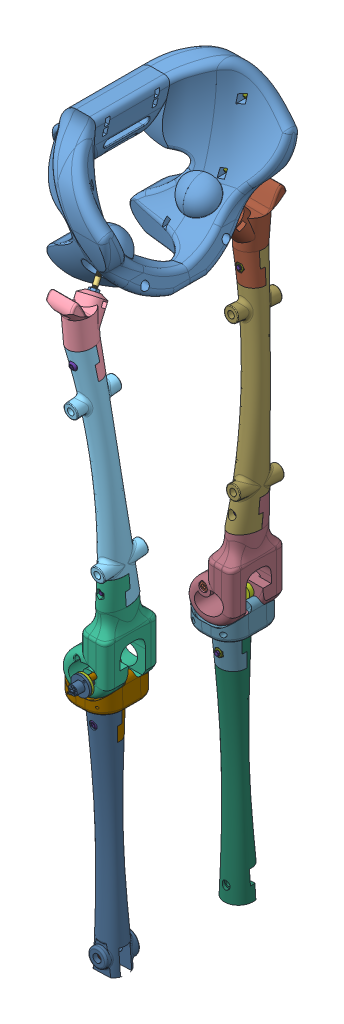
SolidWorks assembly 10_BipedalRobot_Assembly_wHardware, configuration Default. Lengths in mm.
Overall size (197.88 962.44 296.88).
85 component instances, 30 part files, 145 mates.
Components (placement in the parent):
- 09_BipedalRobot_Assembly-1: 09_BipedalRobot_Assembly [Default] at origin size (197.88 962.44 294.61) (flexible)
  - 02_01_Pelvis-1: 02_01_Pelvis [Default] at origin size (197.88 220.17 282.18)
  - 6630T310_METRIC BLACK POLYPROPYLENE BALL KNOB-1: 6630T310_METRIC BLACK POLYPROPYLENE BALL KNOB [6630T31] at (-58.671 -58.8069 72.4936) x (0.804974 0.48308 0.344458) z (-0.194905 0.763657 -0.6155) size (38 38 37.9)
  - 92997A108_CORROSION-RESISTANT SETUP STUD-1: 92997A108_CORROSION-RESISTANT SETUP STUD [92997A108] at (-55.0653 -72.9345 83.8804) x (0.017759 0.630179 0.776247) z (0.194905 -0.763657 0.6155) size (6.34 6.15 50.8)
  - 03_02_FemurHead_Right-1: 03_02_FemurHead_Right [Default] at (-45.3395 -121.5667 106.123) x (1 0 0) z (0 -0.087156 0.996195) size (46.92 105.86 63.35)
  - 03_01_FemurBone_Right-1: 03_01_FemurBone_Right [Default] at (-44.1058 -425.8587 87.0078) x (1 0 0) z (0 -0.087156 0.996195) size (54.81 304.92 60)
  - 04_01_KneeTop_Right-1: 04_01_KneeTop_Right [Default] at (-35.6321 -504.5163 84.7583) size (77.56 157.24 74.14)
  - 04_05_BackLink-1: 04_05_BackLink [Default] at (-42.5577 -521.5571 84.8583) x (0.712112 0.702066 0) z (0 0 1) size (62.75 16 5.9)
  - 04_06_FrontLink-1: 04_06_FrontLink [Default] at (-31.6099 -512.6089 78.7583) x (0.469804 -0.882771 0) z (0 0 1) size (67.43 16 3.9)
  - 04_02_KneeBottom_Right-1: 04_02_KneeBottom_Right [Default] at (-43.0474 -546.2764 84.7583) x (0.999391 0.034899 0) z (0 0 1) size (78.49 85.12 75.75)
  - 05_01_Tibial_Right-1: 05_01_Tibial_Right [Default] at (-42.6984 -556.2703 84.7583) x (0.999391 0.034899 0) z (0 0 1) size (38.19 305.23 41.5)
  - 6630T310_METRIC BLACK POLYPROPYLENE BALL KNOB-2: 6630T310_METRIC BLACK POLYPROPYLENE BALL KNOB [6630T31] at (-58.671 -58.8069 -72.4936) x (0.963134 0.030376 0.2673) z (-0.194905 0.763657 0.6155) size (38 38 37.9)
  - 92997A108_CORROSION-RESISTANT SETUP STUD-2: 92997A108_CORROSION-RESISTANT SETUP STUD [92997A108] at (-55.0653 -72.9345 -83.8804) x (-0.54916 -0.604916 0.576628) z (-0.194905 0.763657 0.6155) size (6.34 6.15 50.8)
  - 03_04_FemurHead_Left-1: 03_04_FemurHead_Left [Default] at (-45.3395 -121.5667 -106.123) x (1 0 0) z (0 0.087156 0.996195) size (46.92 105.86 63.35)
  - 03_03_FemurBone_Left-1: 03_03_FemurBone_Left [Default] at (-44.1058 -425.8587 -87.0078) x (1 0 0) z (0 0.087156 0.996195) size (54.81 304.92 60)
  - 04_03_KneeTop_Left-1: 04_03_KneeTop_Left [Default] at (-35.6321 -504.5163 -84.7583) size (77.56 157.24 74.14)
  - 04_05_BackLink-2: 04_05_BackLink [Default] at (-42.5577 -521.5571 -90.7583) x (0.712112 0.702066 0) z (0 0 1) size (62.75 16 5.9)
  - 04_06_FrontLink-2: 04_06_FrontLink [Default] at (-31.6099 -512.6089 -82.6583) x (-0.469804 0.882771 0) z (0 0 1) size (67.43 16 3.9)
  - 04_04_KneeBottom_Left-1: 04_04_KneeBottom_Left [Default] at (-43.0474 -546.2764 -84.8583) x (0.999391 0.034899 0) z (0 0 1) size (78.49 85.12 75.75)
  - 05_02_Tibial_Left-1: 05_02_Tibial_Left [Default] at (-42.6984 -556.2703 -84.8583) x (0.999391 0.034899 0) z (0 0 1) size (38.19 304.9 38.19)
- 94645A205_HIGH-STRENGTH STEEL NYLON-INSERT LOCKNUT-1: 94645A205_HIGH-STRENGTH STEEL NYLON-INSERT LOCKNUT [94645A205] at (-47.544 52.8275 110.8479) x (0 -1 0) z (0 0 1) size (10 6.41 11.55)
- 94645A205_HIGH-STRENGTH STEEL NYLON-INSERT LOCKNUT-2: 94645A205_HIGH-STRENGTH STEEL NYLON-INSERT LOCKNUT [94645A205] at (-47.544 -21.0136 84.8541) x (0 -1 0) z (0 0 1) size (10 6.41 11.55)
- 94645A205_HIGH-STRENGTH STEEL NYLON-INSERT LOCKNUT-4: 94645A205_HIGH-STRENGTH STEEL NYLON-INSERT LOCKNUT [94645A205] at (-74.544 -75.4386 54.7323) x (0 1 0) z (0 0 1) size (10 6.41 11.55)
- 94645A205_HIGH-STRENGTH STEEL NYLON-INSERT LOCKNUT-6: 94645A205_HIGH-STRENGTH STEEL NYLON-INSERT LOCKNUT [94645A205] at (-47.544 52.8275 -110.8479) x (0 1 0) z (0 0 -1) size (10 6.41 11.55)
- 94645A205_HIGH-STRENGTH STEEL NYLON-INSERT LOCKNUT-8: 94645A205_HIGH-STRENGTH STEEL NYLON-INSERT LOCKNUT [94645A205] at (-47.544 -21.0136 -84.8541) x (0 1 0) z (0 0 -1) size (10 6.41 11.55)
- 94645A205_HIGH-STRENGTH STEEL NYLON-INSERT LOCKNUT-10: 94645A205_HIGH-STRENGTH STEEL NYLON-INSERT LOCKNUT [94645A205] at (-74.544 -75.4386 -54.7323) x (0 1 0) z (0 0 1) size (10 6.41 11.55)
- 94645A205_HIGH-STRENGTH STEEL NYLON-INSERT LOCKNUT-12: 94645A205_HIGH-STRENGTH STEEL NYLON-INSERT LOCKNUT [94645A205] at (-104.3146 69.6752 36.5) x (0 1 0) z (-1 0 0) size (10 6.41 11.55)
- 94645A205_HIGH-STRENGTH STEEL NYLON-INSERT LOCKNUT-14: 94645A205_HIGH-STRENGTH STEEL NYLON-INSERT LOCKNUT [94645A205] at (-121.884 56.6312 36.5) x (0 1 0) z (-1 0 0) size (10 6.41 11.55)
- 94645A205_HIGH-STRENGTH STEEL NYLON-INSERT LOCKNUT-16: 94645A205_HIGH-STRENGTH STEEL NYLON-INSERT LOCKNUT [94645A205] at (-121.884 56.6312 -30.5) x (0 1 0) z (-1 0 0) size (10 6.41 11.55)
- 94645A205_HIGH-STRENGTH STEEL NYLON-INSERT LOCKNUT-18: 94645A205_HIGH-STRENGTH STEEL NYLON-INSERT LOCKNUT [94645A205] at (-104.3146 69.6752 -30.5) x (0 1 0) z (-1 0 0) size (10 6.41 11.55)
- 94645A205_HIGH-STRENGTH STEEL NYLON-INSERT LOCKNUT-20: 94645A205_HIGH-STRENGTH STEEL NYLON-INSERT LOCKNUT [94645A205] at (-51.8494 -85.5349 94.0361) x (0.194905 0.645175 0.738757) z (0.961262 0.024023 -0.274588) size (10 6.41 11.55)
- 94645A205_HIGH-STRENGTH STEEL NYLON-INSERT LOCKNUT-22: 94645A205_HIGH-STRENGTH STEEL NYLON-INSERT LOCKNUT [94645A205] at (-51.8494 -85.5349 -94.0361) x (0.194905 0.645175 -0.738757) z (-0.961262 -0.024023 -0.274588) size (10 6.41 11.55)
- 94645A205_HIGH-STRENGTH STEEL NYLON-INSERT LOCKNUT-24: 94645A205_HIGH-STRENGTH STEEL NYLON-INSERT LOCKNUT [94645A205] at (-30.2115 -92.3012 -13.5) x (0.866025 -0.5 0) z (0.5 0.866025 0) size (10 6.41 11.55)
- 94645A205_HIGH-STRENGTH STEEL NYLON-INSERT LOCKNUT-26: 94645A205_HIGH-STRENGTH STEEL NYLON-INSERT LOCKNUT [94645A205] at (-41.8015 -140.2036 100.5688) x (0.866025 -0.498097 -0.043578) z (0.5 0.86273 0.075479) size (10 6.41 11.55)
- 94645A205_HIGH-STRENGTH STEEL NYLON-INSERT LOCKNUT-28: 94645A205_HIGH-STRENGTH STEEL NYLON-INSERT LOCKNUT [94645A205] at (-41.8015 -140.2036 -100.5688) x (0.866025 -0.498097 0.043578) z (-0.5 -0.86273 0.075479) size (10 6.41 11.55)
- 94645A205_HIGH-STRENGTH STEEL NYLON-INSERT LOCKNUT-30: 94645A205_HIGH-STRENGTH STEEL NYLON-INSERT LOCKNUT [94645A205] at (-23.6321 -408.0461 -101.9838) x (1 0 0) z (0 0.996195 -0.087156) size (10 6.41 11.55)
- 94645A205_HIGH-STRENGTH STEEL NYLON-INSERT LOCKNUT-36: 94645A205_HIGH-STRENGTH STEEL NYLON-INSERT LOCKNUT [94645A205] at (-41.8513 -575.3023 71.7583) x (0.999391 0.034899 0) z (-0.034899 0.999391 0) size (10 6.41 11.55)
- 94645A205_HIGH-STRENGTH STEEL NYLON-INSERT LOCKNUT-39: 94645A205_HIGH-STRENGTH STEEL NYLON-INSERT LOCKNUT [94645A205] at (-23.6321 -408.0461 101.9838) x (-0.5 0.86273 0.075479) z (0.866025 0.498097 0.043578) size (10 6.41 11.55)
- 94645A205_HIGH-STRENGTH STEEL NYLON-INSERT LOCKNUT-41: 94645A205_HIGH-STRENGTH STEEL NYLON-INSERT LOCKNUT [94645A205] at (-41.8513 -575.3023 -71.8583) x (0.999391 0.034899 0) z (0.034899 -0.999391 0) size (10 6.41 11.55)
- 91239A330_CLASS 10.9 STL BUTTON-HEAD SOCKET CAP SCREW-1: 91239A330_CLASS 10.9 STL BUTTON-HEAD SOCKET CAP SCREW [91239A330] at (-121.884 56.6312 66.8) size (10.5 10.5 38.95)
- 91239A330_CLASS 10.9 STL BUTTON-HEAD SOCKET CAP SCREW-2: 91239A330_CLASS 10.9 STL BUTTON-HEAD SOCKET CAP SCREW [91239A330] at (-77.844 52.8275 110.8479) x (0 0 1) z (-1 0 0) size (10.5 10.5 38.95)
- 91239A330_CLASS 10.9 STL BUTTON-HEAD SOCKET CAP SCREW-4: 91239A330_CLASS 10.9 STL BUTTON-HEAD SOCKET CAP SCREW [91239A330] at (-104.3146 69.6752 66.8) x (0.959125 0.282984 0) z (0 0 1) size (10.5 10.5 38.95)
- 91239A330_CLASS 10.9 STL BUTTON-HEAD SOCKET CAP SCREW-6: 91239A330_CLASS 10.9 STL BUTTON-HEAD SOCKET CAP SCREW [91239A330] at (-104.3146 69.6752 -66.8) x (-0.5 0.866025 0) z (0 0 -1) size (10.5 10.5 38.95)
- 91239A330_CLASS 10.9 STL BUTTON-HEAD SOCKET CAP SCREW-8: 91239A330_CLASS 10.9 STL BUTTON-HEAD SOCKET CAP SCREW [91239A330] at (-121.884 56.6312 -66.8) x (-0.642788 0.766044 0) z (0 0 -1) size (10.5 10.5 38.95)
- 91239A330_CLASS 10.9 STL BUTTON-HEAD SOCKET CAP SCREW-10: 91239A330_CLASS 10.9 STL BUTTON-HEAD SOCKET CAP SCREW [91239A330] at (-77.844 52.8275 -110.8479) x (0 0 1) z (-1 0 0) size (10.5 10.5 38.95)
- 91239A330_CLASS 10.9 STL BUTTON-HEAD SOCKET CAP SCREW-12: 91239A330_CLASS 10.9 STL BUTTON-HEAD SOCKET CAP SCREW [91239A330] at (-77.844 -21.0136 -84.8541) x (0 0 1) z (-1 0 0) size (10.5 10.5 38.95)
- 91239A330_CLASS 10.9 STL BUTTON-HEAD SOCKET CAP SCREW-14: 91239A330_CLASS 10.9 STL BUTTON-HEAD SOCKET CAP SCREW [91239A330] at (-77.844 -21.0136 84.8541) x (0 0 1) z (-1 0 0) size (10.5 10.5 38.95)
- 91239A330_CLASS 10.9 STL BUTTON-HEAD SOCKET CAP SCREW-16: 91239A330_CLASS 10.9 STL BUTTON-HEAD SOCKET CAP SCREW [91239A330] at (-44.244 -75.4386 -54.7323) x (0 0.171049 -0.985262) z (1 0 0) size (10.5 10.5 38.95)
- 91239A330_CLASS 10.9 STL BUTTON-HEAD SOCKET CAP SCREW-18: 91239A330_CLASS 10.9 STL BUTTON-HEAD SOCKET CAP SCREW [91239A330] at (-44.244 -75.4386 54.7323) x (0 0 -1) z (1 0 0) size (10.5 10.5 38.95)
- 91239A330_CLASS 10.9 STL BUTTON-HEAD SOCKET CAP SCREW-20: 91239A330_CLASS 10.9 STL BUTTON-HEAD SOCKET CAP SCREW [91239A330] at (-30.2115 -92.3012 16.8) x (0.985697 -0.168526 0) z (0 0 1) size (10.5 10.5 38.95)
- 91239A330_CLASS 10.9 STL BUTTON-HEAD SOCKET CAP SCREW-22: 91239A330_CLASS 10.9 STL BUTTON-HEAD SOCKET CAP SCREW [91239A330] at (-41.8015 -142.9042 131.4369) x (0.92579 -0.376599 -0.032948) z (0 -0.087156 0.996195) size (10.5 10.5 38.95)
- 91239A330_CLASS 10.9 STL BUTTON-HEAD SOCKET CAP SCREW-24: 91239A330_CLASS 10.9 STL BUTTON-HEAD SOCKET CAP SCREW [91239A330] at (-41.8015 -142.9042 -131.4369) x (-0.916799 -0.39783 0.034806) z (0 -0.087156 -0.996195) size (10.5 10.5 38.95)
- 91239A330_CLASS 10.9 STL BUTTON-HEAD SOCKET CAP SCREW-26: 91239A330_CLASS 10.9 STL BUTTON-HEAD SOCKET CAP SCREW [91239A330] at (-23.6321 -405.415 -71.9097) x (0.92535 -0.377672 0.033042) z (0 0.087156 0.996195) size (10.5 10.5 38.95)
- 91239A330_CLASS 10.9 STL BUTTON-HEAD SOCKET CAP SCREW-28: 91239A330_CLASS 10.9 STL BUTTON-HEAD SOCKET CAP SCREW [91239A330] at (-23.6321 -405.415 71.9097) x (-0.509415 -0.857247 -0.074999) z (0 0.087156 -0.996195) size (10.5 10.5 38.95)
- 91239A330_CLASS 10.9 STL BUTTON-HEAD SOCKET CAP SCREW-30: 91239A330_CLASS 10.9 STL BUTTON-HEAD SOCKET CAP SCREW [91239A330] at (-41.8513 -575.3023 -102.1583) x (-0.5 -0.866025 0) z (0 0 -1) size (10.5 10.5 38.95)
- 91239A330_CLASS 10.9 STL BUTTON-HEAD SOCKET CAP SCREW-32: 91239A330_CLASS 10.9 STL BUTTON-HEAD SOCKET CAP SCREW [91239A330] at (-41.8513 -575.3023 102.0583) x (-0.675882 0.73701 0) z (0 0 1) size (10.5 10.5 38.95)
- 91595A476_METRIC ALLOY STEEL DOWEL PIN-1: 91595A476_METRIC ALLOY STEEL DOWEL PIN [91595A476] at (-60.794 24.9417 100.1676) x (1 0 0) z (0 0.020434 0.999791) size (40 6 6)
- 91595A476_METRIC ALLOY STEEL DOWEL PIN-2: 91595A476_METRIC ALLOY STEEL DOWEL PIN [91595A476] at (-60.794 -3.0834 90.0569) x (1 0 0) z (0 -0.138344 0.990384) size (40 6 6)
- 91595A476_METRIC ALLOY STEEL DOWEL PIN-4: 91595A476_METRIC ALLOY STEEL DOWEL PIN [91595A476] at (-60.794 -93.1682 40.0283) x (1 0 0) z (0 -0.263326 0.964707) size (40 6 6)
- 91595A476_METRIC ALLOY STEEL DOWEL PIN-6: 91595A476_METRIC ALLOY STEEL DOWEL PIN [91595A476] at (-60.794 -93.1682 -40.0283) x (1 0 0) z (0 -0.780184 0.62555) size (40 6 6)
- 91595A476_METRIC ALLOY STEEL DOWEL PIN-8: 91595A476_METRIC ALLOY STEEL DOWEL PIN [91595A476] at (-61.544 -3.0834 -90.0569) x (-1 0 0) z (0 0.779019 -0.627) size (40 6 6)
- 91595A476_METRIC ALLOY STEEL DOWEL PIN-10: 91595A476_METRIC ALLOY STEEL DOWEL PIN [91595A476] at (-60.794 24.9417 -100.1676) x (1 0 0) z (0 -0.947084 0.320986) size (40 6 6)
- 90695A038_CLASS 04 STEEL THIN HEX NUT - DIN 439B-1: 90695A038_CLASS 04 STEEL THIN HEX NUT - DIN 439B [90695A038] at (-53.3306 -79.7311 89.3583) x (0.978461 0.194905 -0.06802) z (-0.06802 0.6155 0.785196) size (10 3.98 11.55)
- 90695A038_CLASS 04 STEEL THIN HEX NUT - DIN 439B-2: 90695A038_CLASS 04 STEEL THIN HEX NUT - DIN 439B [90695A038] at (-53.3306 -79.7311 -89.3583) x (0.826706 -0.20978 0.522062) z (-0.527796 -0.61059 0.590433) size (10 3.98 11.55)
- 94510A255_BRASS SCREW-TO-EXPAND INSERTS-4: 94510A255_BRASS SCREW-TO-EXPAND INSERTS [94510A255] at (-43.6921 -489.9063 48.7629) x (-0.34202 0.939693 0) z (-0.939693 -0.34202 0) size (9.53 13.25 9.53)
- 94510A255_BRASS SCREW-TO-EXPAND INSERTS-6: 94510A255_BRASS SCREW-TO-EXPAND INSERTS [94510A255] at (-43.6921 -489.9063 -48.7629) x (-0.130134 -0.991496 0) z (-0.991496 0.130134 0) size (9.53 13.25 9.53)
- 97493A126_ METRIC PARTIALLY THREADED STUDS-1: 97493A126_ METRIC PARTIALLY THREADED STUDS [97493A126] at (-25.9121 -505.1463 -107.6583) x (-0.1 0.994987 0) z (0 0 1) size (6.22 6.14 30.07)
- 97493A126_ METRIC PARTIALLY THREADED STUDS-2: 97493A126_ METRIC PARTIALLY THREADED STUDS [97493A126] at (-43.6921 -489.9063 -59.8583) x (0.997236 0.074297 0) z (0 0 -1) size (6.22 6.14 30.07)
- 97493A126_ METRIC PARTIALLY THREADED STUDS-4: 97493A126_ METRIC PARTIALLY THREADED STUDS [97493A126] at (-43.6921 -489.9063 59.8583) x (0.989622 0.143697 0) z (0 0 1) size (6.22 6.14 30.07)
- 97493A126_ METRIC PARTIALLY THREADED STUDS-9: 97493A126_ METRIC PARTIALLY THREADED STUDS [97493A126] at (-19.5277 -535.3116 92.5583) x (-1 0 0) z (0 0 -1) size (6.22 6.14 30.07)
- 97493A126_ METRIC PARTIALLY THREADED STUDS-10: 97493A126_ METRIC PARTIALLY THREADED STUDS [97493A126] at (-59.2033 -537.9679 92.5583) x (-0.987351 -0.158553 0) z (0 0 -1) size (6.22 6.14 30.07)
- 97493A126_ METRIC PARTIALLY THREADED STUDS-12: 97493A126_ METRIC PARTIALLY THREADED STUDS [97493A126] at (-19.5277 -535.3116 -92.6583) x (-0.994367 -0.105992 0) z (0 0 1) size (6.22 6.14 30.07)
- 97493A126_ METRIC PARTIALLY THREADED STUDS-14: 97493A126_ METRIC PARTIALLY THREADED STUDS [97493A126] at (-59.2033 -537.9679 -92.6583) x (-0.999918 -0.012843 0) z (0 0 1) size (6.22 6.14 30.07)
- 2705T122_LIGHT DUTY DRY-RUNNING FLANGED SLEEVE BEARING-1: 2705T122_LIGHT DUTY DRY-RUNNING FLANGED SLEEVE BEARING [2705T122] at (-25.9121 -505.1463 122.0083) x (1 0 0) z (0 1 0) size (12 10 12)
- 2705T122_LIGHT DUTY DRY-RUNNING FLANGED SLEEVE BEARING-2: 2705T122_LIGHT DUTY DRY-RUNNING FLANGED SLEEVE BEARING [2705T122] at (-25.9121 -505.1463 90.5083) x (1 0 0) z (0 -1 0) size (12 10 12)
- 91828A251_TYPE 18-8 STAINLESS STEEL HEX NUT-1: 91828A251_TYPE 18-8 STAINLESS STEEL HEX NUT [91828A251] at (-25.9121 -505.1463 124.5083) x (0.288427 -0.957502 0) z (0 0 1) size (10 11.55 5.57)
- 91287A344_18-8 Stainless Steel Hex Head Screw-1: 91287A344_18-8 Stainless Steel Hex Head Screw [91287A344] at (-25.9121 -505.1463 110.3583) x (-0.964063 0.265674 0) z (0 0 -1) size (10 11.55 54.58)
- Copy of Part2-1: Copy of Part2 [Default] at origin size (25.4 25.4 3)
- 97163A107_TAPERED HEAT-SET INSERTS FOR PLASTIC -1: 97163A107_TAPERED HEAT-SET INSERTS FOR PLASTIC  [97163A107] at (-31.1621 -513.0938 122.0123) x (1 0 0) z (0 -1 0) size (4.37 7.52 4.37)
- Part3-1: Part3 [Default] at origin
- Part4-1: Part4 [Default] at origin size (18.77 25.26 7.5)
- MAE3-X-236-220-7-X-1: MAE3-X-236-220-7-X [Default] at (-25.9121 -505.1463 131.7503) x (0.551181 0.834386 0) z (0.834386 -0.551181 0) size (25.15 17.82 25.15)
- 97163A107_TAPERED HEAT-SET INSERTS FOR PLASTIC -2: 97163A107_TAPERED HEAT-SET INSERTS FOR PLASTIC  [97163A107] at (-20.6621 -497.1987 122.0123) x (1 0 0) z (0 -1 0) size (4.37 7.52 4.37)
- 60355K450_BALL BEARING-1: 60355K450_BALL BEARING [60355K45] at (-32.759 -840.8968 67.1864) size (22.23 22.23 7.14)
- 60355K450_BALL BEARING-2: 60355K450_BALL BEARING [60355K45] at (-32.759 -840.8968 96.1864) size (22.23 22.23 7.14)
Mates (geometry in assembly coordinates):
- Coincident1: coincident anti-aligned: plane of 09_BipedalRobot_Assembly-1/02_01_Pelvis-1 through (-47.544 0 0) normal (1 0 0); plane of 94645A205_HIGH-STRENGTH STEEL NYLON-INSERT LOCKNUT-1 through (-47.544 47.8275 107.9612) normal (-1 0 0)
- Parallel1: parallel anti-aligned: plane of 09_BipedalRobot_Assembly-1/02_01_Pelvis-1 through (-41.044 57.9775 107.8746) normal (0 -1 0); plane of 94645A205_HIGH-STRENGTH STEEL NYLON-INSERT LOCKNUT-1 through (-41.544 57.8275 107.9612) normal (0 1 0)
- Concentric4: concentric anti-aligned: circle of 09_BipedalRobot_Assembly-1/02_01_Pelvis-1; circle of 94645A205_HIGH-STRENGTH STEEL NYLON-INSERT LOCKNUT-1
- Coincident3: coincident anti-aligned: plane of 09_BipedalRobot_Assembly-1/02_01_Pelvis-1 through (-47.544 0 0) normal (1 0 0); plane of 94645A205_HIGH-STRENGTH STEEL NYLON-INSERT LOCKNUT-2 through (-47.544 -26.0136 81.9674) normal (-1 0 0)
- Parallel2: parallel anti-aligned: plane of 09_BipedalRobot_Assembly-1/02_01_Pelvis-1 through (-41.044 -15.8636 81.8808) normal (0 -1 0); plane of 94645A205_HIGH-STRENGTH STEEL NYLON-INSERT LOCKNUT-2 through (-41.544 -16.0136 81.9674) normal (0 1 0)
- Concentric5: concentric anti-aligned: circle of 09_BipedalRobot_Assembly-1/02_01_Pelvis-1; circle of 94645A205_HIGH-STRENGTH STEEL NYLON-INSERT LOCKNUT-2
- Parallel3: parallel anti-aligned: plane of 09_BipedalRobot_Assembly-1/02_01_Pelvis-1 through (-81.044 -80.5886 57.7056) normal (0 1 0); plane of 94645A205_HIGH-STRENGTH STEEL NYLON-INSERT LOCKNUT-4 through (-80.544 -80.4386 51.8455) normal (0 -1 0)
- Concentric6: concentric anti-aligned: circle of 09_BipedalRobot_Assembly-1/02_01_Pelvis-1; circle of 94645A205_HIGH-STRENGTH STEEL NYLON-INSERT LOCKNUT-4
- Coincident5: coincident anti-aligned: plane of 09_BipedalRobot_Assembly-1/02_01_Pelvis-1 through (-74.544 0 0) normal (-1 0 0); plane of 94645A205_HIGH-STRENGTH STEEL NYLON-INSERT LOCKNUT-4 through (-74.544 -70.4386 51.8455) normal (1 0 0)
- Coincident6: coincident anti-aligned: plane of 09_BipedalRobot_Assembly-1/02_01_Pelvis-1 through (-47.544 0 0) normal (1 0 0); plane of 94645A205_HIGH-STRENGTH STEEL NYLON-INSERT LOCKNUT-6 through (-47.544 57.8275 -107.9612) normal (-1 0 0)
- Parallel4: parallel anti-aligned: plane of 09_BipedalRobot_Assembly-1/02_01_Pelvis-1 through (-41.044 47.6775 -113.8213) normal (0 1 0); plane of 94645A205_HIGH-STRENGTH STEEL NYLON-INSERT LOCKNUT-6 through (-41.544 47.8275 -107.9612) normal (0 -1 0)
- Concentric7: concentric aligned: circle of 09_BipedalRobot_Assembly-1/02_01_Pelvis-1; circle of 94645A205_HIGH-STRENGTH STEEL NYLON-INSERT LOCKNUT-6
- Coincident7: coincident anti-aligned: plane of 09_BipedalRobot_Assembly-1/02_01_Pelvis-1 through (-47.544 0 0) normal (1 0 0); plane of 94645A205_HIGH-STRENGTH STEEL NYLON-INSERT LOCKNUT-8 through (-47.544 -16.0136 -81.9674) normal (-1 0 0)
- Parallel5: parallel anti-aligned: plane of 09_BipedalRobot_Assembly-1/02_01_Pelvis-1 through (-41.044 -26.1636 -87.8275) normal (0 1 0); plane of 94645A205_HIGH-STRENGTH STEEL NYLON-INSERT LOCKNUT-8 through (-41.544 -26.0136 -81.9674) normal (0 -1 0)
- Concentric8: concentric aligned: circle of 09_BipedalRobot_Assembly-1/02_01_Pelvis-1; circle of 94645A205_HIGH-STRENGTH STEEL NYLON-INSERT LOCKNUT-8
- Coincident8: coincident anti-aligned: plane of 09_BipedalRobot_Assembly-1/02_01_Pelvis-1 through (-74.544 0 0) normal (-1 0 0); plane of 94645A205_HIGH-STRENGTH STEEL NYLON-INSERT LOCKNUT-10 through (-74.544 -70.4386 -57.619) normal (1 0 0)
- Parallel6: parallel anti-aligned: plane of 09_BipedalRobot_Assembly-1/02_01_Pelvis-1 through (-81.044 -80.5886 -57.7056) normal (0 1 0); plane of 94645A205_HIGH-STRENGTH STEEL NYLON-INSERT LOCKNUT-10 through (-80.544 -80.4386 -57.619) normal (0 -1 0)
- Concentric11: concentric aligned: circle of 09_BipedalRobot_Assembly-1/02_01_Pelvis-1; circle of 94645A205_HIGH-STRENGTH STEEL NYLON-INSERT LOCKNUT-10
- Coincident9: coincident anti-aligned: plane of 09_BipedalRobot_Assembly-1/02_01_Pelvis-1 through (0 0 36.5) normal (0 0 -1); plane of 94645A205_HIGH-STRENGTH STEEL NYLON-INSERT LOCKNUT-12 through (-101.4278 74.6752 36.5) normal (0 0 1)
- Parallel7: parallel anti-aligned: plane of 09_BipedalRobot_Assembly-1/02_01_Pelvis-1 through (-101.3412 64.5252 30.5) normal (0 1 0); plane of 94645A205_HIGH-STRENGTH STEEL NYLON-INSERT LOCKNUT-12 through (-101.4278 64.6752 30.5) normal (0 -1 0)
- Concentric12: concentric anti-aligned: circle of 09_BipedalRobot_Assembly-1/02_01_Pelvis-1; circle of 94645A205_HIGH-STRENGTH STEEL NYLON-INSERT LOCKNUT-12
- Coincident10: coincident anti-aligned: plane of 09_BipedalRobot_Assembly-1/02_01_Pelvis-1 through (0 0 36.5) normal (0 0 -1); plane of 94645A205_HIGH-STRENGTH STEEL NYLON-INSERT LOCKNUT-14 through (-118.9973 61.6312 36.5) normal (0 0 1)
- Parallel8: parallel anti-aligned: plane of 09_BipedalRobot_Assembly-1/02_01_Pelvis-1 through (-118.9107 51.4812 30.5) normal (0 1 0); plane of 94645A205_HIGH-STRENGTH STEEL NYLON-INSERT LOCKNUT-14 through (-118.9973 51.6312 30.5) normal (0 -1 0)
- Concentric13: concentric anti-aligned: circle of 09_BipedalRobot_Assembly-1/02_01_Pelvis-1; circle of 94645A205_HIGH-STRENGTH STEEL NYLON-INSERT LOCKNUT-14
- Coincident11: coincident anti-aligned: plane of 09_BipedalRobot_Assembly-1/02_01_Pelvis-1 through (0 0 -30.5) normal (0 0 -1); plane of 94645A205_HIGH-STRENGTH STEEL NYLON-INSERT LOCKNUT-16 through (-118.9973 61.6312 -30.5) normal (0 0 1)
- Parallel9: parallel anti-aligned: plane of 09_BipedalRobot_Assembly-1/02_01_Pelvis-1 through (-118.9107 51.4812 -30.5) normal (0 1 0); plane of 94645A205_HIGH-STRENGTH STEEL NYLON-INSERT LOCKNUT-16 through (-118.9973 51.6312 -36.5) normal (0 -1 0)
- Concentric14: concentric anti-aligned: circle of 09_BipedalRobot_Assembly-1/02_01_Pelvis-1; circle of 94645A205_HIGH-STRENGTH STEEL NYLON-INSERT LOCKNUT-16
- Coincident12: coincident anti-aligned: plane of 09_BipedalRobot_Assembly-1/02_01_Pelvis-1 through (0 0 -30.5) normal (0 0 -1); plane of 94645A205_HIGH-STRENGTH STEEL NYLON-INSERT LOCKNUT-18 through (-101.4278 74.6752 -30.5) normal (0 0 1)
- Parallel10: parallel anti-aligned: plane of 09_BipedalRobot_Assembly-1/02_01_Pelvis-1 through (-101.3412 64.5252 -30.5) normal (0 1 0); plane of 94645A205_HIGH-STRENGTH STEEL NYLON-INSERT LOCKNUT-18 through (-101.4278 64.6752 -36.5) normal (0 -1 0)
- Concentric15: concentric anti-aligned: circle of 09_BipedalRobot_Assembly-1/02_01_Pelvis-1; circle of 94645A205_HIGH-STRENGTH STEEL NYLON-INSERT LOCKNUT-18
- Coincident13: coincident anti-aligned: plane of 09_BipedalRobot_Assembly-1/03_02_FemurHead_Right-1 through (-53.3962 -90.6553 88.173) normal (0.194905 -0.763657 0.6155); plane of 94645A205_HIGH-STRENGTH STEEL NYLON-INSERT LOCKNUT-20 through (-53.6498 -82.3783 98.5226) normal (-0.194905 0.763657 -0.6155)
- Parallel11: parallel anti-aligned: plane of 09_BipedalRobot_Assembly-1/03_02_FemurHead_Right-1 through (-19.7212 -93.0069 85.1522) normal (0.194905 0.645175 0.738757); plane of 94645A205_HIGH-STRENGTH STEEL NYLON-INSERT LOCKNUT-20 through (-54.4294 -93.412 94.828) normal (-0.194905 -0.645175 -0.738757)
- Concentric16: concentric aligned: circle of 09_BipedalRobot_Assembly-1/03_02_FemurHead_Right-1; circle of 94645A205_HIGH-STRENGTH STEEL NYLON-INSERT LOCKNUT-20
- Coincident14: coincident anti-aligned: plane of 09_BipedalRobot_Assembly-1/03_04_FemurHead_Left-1 through (-53.3962 -90.6553 -88.173) normal (0.194905 -0.763657 -0.6155); plane of 94645A205_HIGH-STRENGTH STEEL NYLON-INSERT LOCKNUT-22 through (-48.0999 -82.2396 -96.9372) normal (-0.194905 0.763657 0.6155)
- Parallel12: parallel anti-aligned: plane of 09_BipedalRobot_Assembly-1/03_04_FemurHead_Left-1 through (-19.7212 -93.0069 -85.1522) normal (0.194905 0.645175 -0.738757); plane of 94645A205_HIGH-STRENGTH STEEL NYLON-INSERT LOCKNUT-22 through (-48.8795 -93.2733 -93.2427) normal (-0.194905 -0.645175 0.738757)
- Concentric17: concentric anti-aligned: circle of 09_BipedalRobot_Assembly-1/03_04_FemurHead_Left-1; circle of 94645A205_HIGH-STRENGTH STEEL NYLON-INSERT LOCKNUT-22
- Coincident15: coincident anti-aligned: plane of 09_BipedalRobot_Assembly-1/02_01_Pelvis-1 through (0 0 -13.5) normal (0 0 -1); plane of 94645A205_HIGH-STRENGTH STEEL NYLON-INSERT LOCKNUT-24 through (-27.3247 -97.3012 -13.5) normal (0 0 1)
- Parallel13: parallel anti-aligned: plane of 09_BipedalRobot_Assembly-1/02_01_Pelvis-1 through (-36.1582 -92.3012 -143.5354) normal (0.866025 -0.5 0); plane of 94645A205_HIGH-STRENGTH STEEL NYLON-INSERT LOCKNUT-24 through (-35.985 -92.3012 -19.5) normal (-0.866025 0.5 0)
- Concentric18: concentric aligned: circle of 09_BipedalRobot_Assembly-1/02_01_Pelvis-1; circle of 94645A205_HIGH-STRENGTH STEEL NYLON-INSERT LOCKNUT-24
- Coincident16: coincident anti-aligned: plane of 09_BipedalRobot_Assembly-1/03_02_FemurHead_Right-1 through (-45.3395 -121.2261 102.2291) normal (0 0.087156 -0.996195); plane of 94645A205_HIGH-STRENGTH STEEL NYLON-INSERT LOCKNUT-26 through (-38.9147 -145.1846 100.133) normal (0 -0.087156 0.996195)
- Parallel14: parallel anti-aligned: plane of 09_BipedalRobot_Assembly-1/03_02_FemurHead_Right-1 through (-47.8637 -139.5343 92.9194) normal (0.866025 -0.498097 -0.043578); plane of 94645A205_HIGH-STRENGTH STEEL NYLON-INSERT LOCKNUT-26 through (-47.575 -139.6806 94.5917) normal (-0.866025 0.498097 0.043578)
- Concentric19: concentric aligned: circle of 09_BipedalRobot_Assembly-1/03_02_FemurHead_Right-1; circle of 94645A205_HIGH-STRENGTH STEEL NYLON-INSERT LOCKNUT-26
- Coincident17: coincident anti-aligned: plane of 09_BipedalRobot_Assembly-1/03_04_FemurHead_Left-1 through (-45.3395 -121.2261 -102.2291) normal (0 0.087156 0.996195); plane of 94645A205_HIGH-STRENGTH STEEL NYLON-INSERT LOCKNUT-28 through (-36.028 -140.2036 -100.5688) normal (0 -0.087156 -0.996195)
- Parallel15: parallel anti-aligned: plane of 09_BipedalRobot_Assembly-1/03_04_FemurHead_Left-1 through (-47.8637 -139.5343 -92.9194) normal (0.866025 -0.498097 0.043578); plane of 94645A205_HIGH-STRENGTH STEEL NYLON-INSERT LOCKNUT-28 through (-44.6882 -134.6997 -95.0274) normal (-0.866025 0.498097 -0.043578)
- Concentric20: concentric anti-aligned: circle of 09_BipedalRobot_Assembly-1/03_04_FemurHead_Left-1; circle of 94645A205_HIGH-STRENGTH STEEL NYLON-INSERT LOCKNUT-28
- Coincident18: coincident anti-aligned: plane of 09_BipedalRobot_Assembly-1/04_03_KneeTop_Left-1 through (-35.6321 -505.2791 -93.4771) normal (0 -0.087156 -0.996195); plane of 94645A205_HIGH-STRENGTH STEEL NYLON-INSERT LOCKNUT-30 through (-18.6321 -410.9219 -101.7322) normal (0 0.087156 0.996195)
- Parallel16: parallel anti-aligned: plane of 09_BipedalRobot_Assembly-1/04_03_KneeTop_Left-1 through (-28.8821 -407.1183 -126.1567) normal (1 0 0); plane of 94645A205_HIGH-STRENGTH STEEL NYLON-INSERT LOCKNUT-30 through (-28.6321 -411.4448 -107.7094) normal (-1 0 0)
- Concentric21: concentric anti-aligned: circle of 09_BipedalRobot_Assembly-1/04_03_KneeTop_Left-1; circle of 94645A205_HIGH-STRENGTH STEEL NYLON-INSERT LOCKNUT-30
- Coincident21: coincident anti-aligned: plane of 09_BipedalRobot_Assembly-1/04_02_KneeBottom_Right-1 through (-43.0474 -546.2764 71.7583) normal (0 0 -1); plane of 94645A205_HIGH-STRENGTH STEEL NYLON-INSERT LOCKNUT-36 through (-36.7536 -578.0128 71.7583) normal (0 0 1)
- Parallel19: parallel anti-aligned: plane of 09_BipedalRobot_Assembly-1/04_02_KneeBottom_Right-1 through (-47.2039 -572.4563 46.8849) normal (0.999391 0.034899 0); plane of 94645A205_HIGH-STRENGTH STEEL NYLON-INSERT LOCKNUT-36 through (-46.7476 -578.3618 65.7583) normal (-0.999391 -0.034899 0)
- Concentric24: concentric anti-aligned: circle of 09_BipedalRobot_Assembly-1/04_02_KneeBottom_Right-1; circle of 94645A205_HIGH-STRENGTH STEEL NYLON-INSERT LOCKNUT-36
- Coincident23: coincident anti-aligned: plane of 09_BipedalRobot_Assembly-1/04_01_KneeTop_Right-1 through (-35.6321 -505.2791 93.4771) normal (0 -0.087156 0.996195); plane of 94645A205_HIGH-STRENGTH STEEL NYLON-INSERT LOCKNUT-39 through (-28.6321 -405.1704 102.2354) normal (0 0.087156 -0.996195)
- Parallel21: parallel anti-aligned: plane of 09_BipedalRobot_Assembly-1/04_01_KneeTop_Right-1 through (-23.6321 -416.177 125.3642) normal (-0.5 0.86273 0.075479); plane of 94645A205_HIGH-STRENGTH STEEL NYLON-INSERT LOCKNUT-39 through (-23.6321 -414.3206 107.4578) normal (0.5 -0.86273 -0.075479)
- Concentric26: concentric anti-aligned: cylinder of 09_BipedalRobot_Assembly-1/04_01_KneeTop_Right-1 through (-23.6321 -403.1666 46.2101) axis (0 -0.087156 0.996195) radius 3.25; circle of 94645A205_HIGH-STRENGTH STEEL NYLON-INSERT LOCKNUT-39
- Coincident24: coincident anti-aligned: plane of 09_BipedalRobot_Assembly-1/04_04_KneeBottom_Left-1 through (-43.0474 -546.2764 -71.8583) normal (0 0 1); plane of 94645A205_HIGH-STRENGTH STEEL NYLON-INSERT LOCKNUT-41 through (-36.9551 -572.2428 -71.8583) normal (0 0 -1)
- Parallel22: parallel anti-aligned: plane of 09_BipedalRobot_Assembly-1/04_04_KneeBottom_Left-1 through (-47.2039 -572.4563 -46.9849) normal (0.999391 0.034899 0); plane of 94645A205_HIGH-STRENGTH STEEL NYLON-INSERT LOCKNUT-41 through (-46.949 -572.5918 -65.8583) normal (-0.999391 -0.034899 0)
- Concentric27: concentric aligned: cylinder of 09_BipedalRobot_Assembly-1/04_04_KneeBottom_Left-1 through (-41.8513 -575.3023 -46.9849) axis (0 0 -1) radius 3.25; circle of 94645A205_HIGH-STRENGTH STEEL NYLON-INSERT LOCKNUT-41
- Concentric28: concentric aligned: cylinder of 09_BipedalRobot_Assembly-1/02_01_Pelvis-1 through (-121.884 56.6312 143.5354) axis (0 0 -1) radius 5.375; cylinder of 91239A330_CLASS 10.9 STL BUTTON-HEAD SOCKET CAP SCREW-1 through (-121.884 56.6312 28.5) axis (0 0 -1) radius 3
- Coincident25: coincident anti-aligned: plane of 09_BipedalRobot_Assembly-1/02_01_Pelvis-1 through (-121.884 56.6312 63.5) normal (0 0 1); plane of 91239A330_CLASS 10.9 STL BUTTON-HEAD SOCKET CAP SCREW-1 through (-121.884 51.3812 63.5) normal (0 0 -1)
- Concentric29: concentric aligned: cylinder of 09_BipedalRobot_Assembly-1/02_01_Pelvis-1 through (-187.4808 52.8275 110.8479) axis (1 0 0) radius 5.375; cylinder of 91239A330_CLASS 10.9 STL BUTTON-HEAD SOCKET CAP SCREW-2 through (-39.544 52.8275 110.8479) axis (1 0 0) radius 3
- Coincident26: coincident anti-aligned: plane of 09_BipedalRobot_Assembly-1/02_01_Pelvis-1 through (-74.544 52.8275 110.8479) normal (-1 0 0); plane of 91239A330_CLASS 10.9 STL BUTTON-HEAD SOCKET CAP SCREW-2 through (-74.544 47.5775 110.8479) normal (1 0 0)
- Concentric30: concentric aligned: cylinder of 09_BipedalRobot_Assembly-1/02_01_Pelvis-1 through (-104.3146 69.6752 143.5354) axis (0 0 -1) radius 5.375; cylinder of 91239A330_CLASS 10.9 STL BUTTON-HEAD SOCKET CAP SCREW-4 through (-104.3146 69.6752 28.5) axis (0 0 -1) radius 3
- Coincident27: coincident anti-aligned: plane of 09_BipedalRobot_Assembly-1/02_01_Pelvis-1 through (-104.3146 69.6752 63.5) normal (0 0 1); plane of 91239A330_CLASS 10.9 STL BUTTON-HEAD SOCKET CAP SCREW-4 through (-102.8289 64.6398 63.5) normal (0 0 -1)
- Concentric31: concentric aligned: cylinder of 09_BipedalRobot_Assembly-1/02_01_Pelvis-1 through (-104.3146 69.6752 -143.5354) axis (0 0 1) radius 5.375; cylinder of 91239A330_CLASS 10.9 STL BUTTON-HEAD SOCKET CAP SCREW-6 through (-104.3146 69.6752 -28.5) axis (0 0 1) radius 3
- Coincident28: coincident anti-aligned: plane of 09_BipedalRobot_Assembly-1/02_01_Pelvis-1 through (-104.3146 69.6752 -63.5) normal (0 0 -1); plane of 91239A330_CLASS 10.9 STL BUTTON-HEAD SOCKET CAP SCREW-6 through (-108.8612 67.0502 -63.5) normal (0 0 1)
- Concentric32: concentric aligned: cylinder of 09_BipedalRobot_Assembly-1/02_01_Pelvis-1 through (-121.884 56.6312 -143.5354) axis (0 0 1) radius 5.375; cylinder of 91239A330_CLASS 10.9 STL BUTTON-HEAD SOCKET CAP SCREW-8 through (-121.884 56.6312 -28.5) axis (0 0 1) radius 3
- Coincident29: coincident anti-aligned: plane of 09_BipedalRobot_Assembly-1/02_01_Pelvis-1 through (-121.884 56.6312 -63.5) normal (0 0 -1); plane of 91239A330_CLASS 10.9 STL BUTTON-HEAD SOCKET CAP SCREW-8 through (-125.9058 53.2566 -63.5) normal (0 0 1)
- Concentric33: concentric aligned: cylinder of 09_BipedalRobot_Assembly-1/02_01_Pelvis-1 through (-187.4808 52.8275 -110.8479) axis (1 0 0) radius 5.375; cylinder of 91239A330_CLASS 10.9 STL BUTTON-HEAD SOCKET CAP SCREW-10 through (-39.544 52.8275 -110.8479) axis (1 0 0) radius 3
- Coincident30: coincident anti-aligned: plane of 09_BipedalRobot_Assembly-1/02_01_Pelvis-1 through (-74.544 52.8275 -110.8479) normal (-1 0 0); plane of 91239A330_CLASS 10.9 STL BUTTON-HEAD SOCKET CAP SCREW-10 through (-74.544 47.5775 -110.8479) normal (1 0 0)
- Concentric34: concentric aligned: cylinder of 09_BipedalRobot_Assembly-1/02_01_Pelvis-1 through (-187.4808 -21.0136 -84.8541) axis (1 0 0) radius 5.375; cylinder of 91239A330_CLASS 10.9 STL BUTTON-HEAD SOCKET CAP SCREW-12 through (-39.544 -21.0136 -84.8541) axis (1 0 0) radius 3
- Coincident31: coincident anti-aligned: plane of 09_BipedalRobot_Assembly-1/02_01_Pelvis-1 through (-74.544 -21.0136 -84.8541) normal (-1 0 0); plane of 91239A330_CLASS 10.9 STL BUTTON-HEAD SOCKET CAP SCREW-12 through (-74.544 -26.2636 -84.8541) normal (1 0 0)
- Concentric35: concentric aligned: cylinder of 09_BipedalRobot_Assembly-1/02_01_Pelvis-1 through (-187.4808 -21.0136 84.8541) axis (1 0 0) radius 5.375; cylinder of 91239A330_CLASS 10.9 STL BUTTON-HEAD SOCKET CAP SCREW-14 through (-39.544 -21.0136 84.8541) axis (1 0 0) radius 3
- Coincident32: coincident anti-aligned: plane of 09_BipedalRobot_Assembly-1/02_01_Pelvis-1 through (-74.544 -21.0136 84.8541) normal (-1 0 0); plane of 91239A330_CLASS 10.9 STL BUTTON-HEAD SOCKET CAP SCREW-14 through (-74.544 -26.2636 84.8541) normal (1 0 0)
- Concentric36: concentric aligned: cylinder of 09_BipedalRobot_Assembly-1/02_01_Pelvis-1 through (18.4173 -75.4386 -54.7323) axis (-1 0 0) radius 5.375; cylinder of 91239A330_CLASS 10.9 STL BUTTON-HEAD SOCKET CAP SCREW-16 through (-82.544 -75.4386 -54.7323) axis (-1 0 0) radius 3
- Coincident33: coincident anti-aligned: plane of 09_BipedalRobot_Assembly-1/02_01_Pelvis-1 through (-47.544 -75.4386 -54.7323) normal (1 0 0); plane of 91239A330_CLASS 10.9 STL BUTTON-HEAD SOCKET CAP SCREW-16 through (-47.544 -80.6112 -55.6303) normal (-1 0 0)
- Concentric37: concentric aligned: cylinder of 09_BipedalRobot_Assembly-1/02_01_Pelvis-1 through (18.4173 -75.4386 54.7323) axis (-1 0 0) radius 5.375; cylinder of 91239A330_CLASS 10.9 STL BUTTON-HEAD SOCKET CAP SCREW-18 through (-82.544 -75.4386 54.7323) axis (-1 0 0) radius 3
- Coincident34: coincident anti-aligned: plane of 09_BipedalRobot_Assembly-1/02_01_Pelvis-1 through (-47.544 -75.4386 54.7323) normal (1 0 0); plane of 91239A330_CLASS 10.9 STL BUTTON-HEAD SOCKET CAP SCREW-18 through (-47.544 -80.6886 54.7323) normal (-1 0 0)
- Concentric38: concentric aligned: cylinder of 09_BipedalRobot_Assembly-1/02_01_Pelvis-1 through (-30.2115 -92.3012 143.5354) axis (0 0 -1) radius 5.375; cylinder of 91239A330_CLASS 10.9 STL BUTTON-HEAD SOCKET CAP SCREW-20 through (-30.2115 -92.3012 -21.5) axis (0 0 -1) radius 3
- Coincident35: coincident anti-aligned: plane of 09_BipedalRobot_Assembly-1/02_01_Pelvis-1 through (0 0 13.5) normal (0 0 1); plane of 91239A330_CLASS 10.9 STL BUTTON-HEAD SOCKET CAP SCREW-20 through (-31.0962 -97.4761 13.5) normal (0 0 -1)
- Concentric39: concentric aligned: cylinder of 09_BipedalRobot_Assembly-1/03_01_FemurBone_Right-1 through (-41.8015 -143.4149 137.2744) axis (0 0.087156 -0.996195) radius 5.5; cylinder of 91239A330_CLASS 10.9 STL BUTTON-HEAD SOCKET CAP SCREW-22 through (-41.8015 -139.5661 93.2827) axis (0 0.087156 -0.996195) radius 3
- Coincident36: coincident anti-aligned: plane of 09_BipedalRobot_Assembly-1/03_01_FemurBone_Right-1 through (-41.8015 -142.6166 128.1495) normal (0 -0.087156 0.996195); plane of 91239A330_CLASS 10.9 STL BUTTON-HEAD SOCKET CAP SCREW-22 through (-43.7862 -147.4585 127.7259) normal (0 0.087156 -0.996195)
- Concentric40: concentric aligned: cylinder of 09_BipedalRobot_Assembly-1/03_03_FemurBone_Left-1 through (-41.8015 -143.4149 -137.2744) axis (0 0.087156 0.996195) radius 3.175; cylinder of 91239A330_CLASS 10.9 STL BUTTON-HEAD SOCKET CAP SCREW-24 through (-41.8015 -139.5661 -93.2827) axis (0 0.087156 0.996195) radius 3
- Coincident37: coincident anti-aligned: plane of 09_BipedalRobot_Assembly-1/03_03_FemurBone_Left-1 through (-41.8015 -142.6166 -128.1495) normal (0 -0.087156 -0.996195); plane of 91239A330_CLASS 10.9 STL BUTTON-HEAD SOCKET CAP SCREW-24 through (-39.7049 -147.4114 -127.73) normal (0 0.087156 0.996195)
- Concentric41: concentric aligned: cylinder of 09_BipedalRobot_Assembly-1/03_03_FemurBone_Left-1 through (-23.6321 -404.666 -63.3491) axis (0 -0.087156 -0.996195) radius 5.5; cylinder of 91239A330_CLASS 10.9 STL BUTTON-HEAD SOCKET CAP SCREW-26 through (-23.6321 -408.753 -110.0639) axis (0 -0.087156 -0.996195) radius 3
- Coincident38: coincident anti-aligned: plane of 09_BipedalRobot_Assembly-1/03_03_FemurBone_Left-1 through (-23.6321 -405.7026 -75.1971) normal (0 0.087156 0.996195); plane of 91239A330_CLASS 10.9 STL BUTTON-HEAD SOCKET CAP SCREW-26 through (-25.6225 -410.5422 -74.7737) normal (0 -0.087156 -0.996195)
- Concentric42: concentric aligned: cylinder of 09_BipedalRobot_Assembly-1/03_01_FemurBone_Right-1 through (-23.6321 -404.666 63.3491) axis (0 -0.087156 0.996195) radius 5.5; cylinder of 91239A330_CLASS 10.9 STL BUTTON-HEAD SOCKET CAP SCREW-28 through (-23.6321 -408.753 110.0639) axis (0 -0.087156 0.996195) radius 3
- Coincident39: coincident anti-aligned: plane of 09_BipedalRobot_Assembly-1/03_01_FemurBone_Right-1 through (-23.6321 -405.7026 75.1971) normal (0 0.087156 -0.996195); plane of 91239A330_CLASS 10.9 STL BUTTON-HEAD SOCKET CAP SCREW-28 through (-19.1144 -408.3668 74.964) normal (0 -0.087156 0.996195)
- Concentric43: concentric aligned: cylinder of 09_BipedalRobot_Assembly-1/05_02_Tibial_Left-1 through (-41.8513 -575.3023 -103.9547) axis (0 0 1) radius 5.25; cylinder of 91239A330_CLASS 10.9 STL BUTTON-HEAD SOCKET CAP SCREW-30 through (-41.8513 -575.3023 -63.8583) axis (0 0 1) radius 3
- Coincident40: coincident anti-aligned: plane of 09_BipedalRobot_Assembly-1/05_02_Tibial_Left-1 through (-41.8513 -575.3023 -98.8583) normal (0 0 -1); plane of 91239A330_CLASS 10.9 STL BUTTON-HEAD SOCKET CAP SCREW-30 through (-37.3047 -577.9273 -98.8583) normal (0 0 1)
- Concentric44: concentric anti-aligned: cylinder of 09_BipedalRobot_Assembly-1/05_01_Tibial_Right-1 through (-41.8513 -575.3023 65.6619) axis (0 0 1) radius 3.25; cylinder of 91239A330_CLASS 10.9 STL BUTTON-HEAD SOCKET CAP SCREW-32 through (-41.8513 -575.3023 63.7583) axis (0 0 -1) radius 3
- Coincident41: coincident anti-aligned: plane of 09_BipedalRobot_Assembly-1/05_01_Tibial_Right-1 through (-41.8513 -575.3023 98.7583) normal (0 0 1); plane of 91239A330_CLASS 10.9 STL BUTTON-HEAD SOCKET CAP SCREW-32 through (-37.982 -571.7539 98.7583) normal (0 0 -1)
- Concentric45: concentric aligned: circle of 09_BipedalRobot_Assembly-1/02_01_Pelvis-1; cylinder of 91595A476_METRIC ALLOY STEEL DOWEL PIN-1 through (-80.794 24.9417 100.1676) axis (1 0 0) radius 3
- Coincident42: coincident: circle of 09_BipedalRobot_Assembly-1/02_01_Pelvis-1; plane of 91595A476_METRIC ALLOY STEEL DOWEL PIN-1 through (-40.794 24.9417 100.1676) normal (1 0 0)
- Concentric48: concentric aligned: circle of 09_BipedalRobot_Assembly-1/02_01_Pelvis-1; cylinder of 91595A476_METRIC ALLOY STEEL DOWEL PIN-2 through (-80.794 -3.0834 90.0569) axis (1 0 0) radius 3
- Coincident43: coincident: circle of 09_BipedalRobot_Assembly-1/02_01_Pelvis-1; plane of 91595A476_METRIC ALLOY STEEL DOWEL PIN-2 through (-40.794 -3.0834 90.0569) normal (1 0 0)
- Concentric49: concentric aligned: circle of 09_BipedalRobot_Assembly-1/02_01_Pelvis-1; cylinder of 91595A476_METRIC ALLOY STEEL DOWEL PIN-4 through (-80.794 -93.1682 40.0283) axis (1 0 0) radius 3
- Coincident44: coincident: circle of 09_BipedalRobot_Assembly-1/02_01_Pelvis-1; plane of 91595A476_METRIC ALLOY STEEL DOWEL PIN-4 through (-40.794 -93.1682 40.0283) normal (1 0 0)
- Concentric50: concentric anti-aligned: circle of 09_BipedalRobot_Assembly-1/02_01_Pelvis-1; cylinder of 91595A476_METRIC ALLOY STEEL DOWEL PIN-6 through (-80.794 -93.1682 -40.0283) axis (1 0 0) radius 3
- Coincident45: coincident: circle of 09_BipedalRobot_Assembly-1/02_01_Pelvis-1; plane of 91595A476_METRIC ALLOY STEEL DOWEL PIN-6 through (-40.794 -93.1682 -40.0283) normal (1 0 0)
- Concentric51: concentric aligned: circle of 09_BipedalRobot_Assembly-1/02_01_Pelvis-1; cylinder of 91595A476_METRIC ALLOY STEEL DOWEL PIN-8 through (-41.544 -3.0834 -90.0569) axis (-1 0 0) radius 3
- Coincident46: coincident: circle of 09_BipedalRobot_Assembly-1/02_01_Pelvis-1; plane of 91595A476_METRIC ALLOY STEEL DOWEL PIN-8 through (-81.544 -3.0834 -90.0569) normal (-1 0 0)
- Concentric52: concentric anti-aligned: circle of 09_BipedalRobot_Assembly-1/02_01_Pelvis-1; cylinder of 91595A476_METRIC ALLOY STEEL DOWEL PIN-10 through (-80.794 24.9417 -100.1676) axis (1 0 0) radius 3
- Coincident47: coincident: circle of 09_BipedalRobot_Assembly-1/02_01_Pelvis-1; plane of 91595A476_METRIC ALLOY STEEL DOWEL PIN-10 through (-40.794 24.9417 -100.1676) normal (1 0 0)
- Concentric53: concentric anti-aligned: cylinder of 09_BipedalRobot_Assembly-1/92997A108_CORROSION-RESISTANT SETUP STUD-1 through (-50.1927 -92.0259 99.2679) axis (0.194905 -0.763657 0.6155) radius 3.02; circle of 90695A038_CLASS 04 STEEL THIN HEX NUT - DIN 439B-1
- Coincident48: coincident anti-aligned: plane of 09_BipedalRobot_Assembly-1/03_02_FemurHead_Right-1 through (-53.0188 -80.9529 90.3431) normal (-0.194905 0.763657 -0.6155); plane of 90695A038_CLASS 04 STEEL THIN HEX NUT - DIN 439B-1 through (-57.7147 -83.7042 88.4165) normal (0.194905 -0.763657 0.6155)
- Concentric54: concentric aligned: cylinder of 09_BipedalRobot_Assembly-1/92997A108_CORROSION-RESISTANT SETUP STUD-2 through (-59.9379 -53.8431 -68.4929) axis (-0.194905 0.763657 0.6155) radius 3.02; circle of 90695A038_CLASS 04 STEEL THIN HEX NUT - DIN 439B-2
- Coincident49: coincident anti-aligned: plane of 09_BipedalRobot_Assembly-1/03_04_FemurHead_Left-1 through (-53.0188 -80.9529 -90.3431) normal (-0.194905 0.763657 0.6155); plane of 90695A038_CLASS 04 STEEL THIN HEX NUT - DIN 439B-2 through (-55.6287 -78.1414 -94.6579) normal (0.194905 -0.763657 -0.6155)
- Concentric57: concentric anti-aligned: circle of 09_BipedalRobot_Assembly-1/04_01_KneeTop_Right-1; circle of 94510A255_BRASS SCREW-TO-EXPAND INSERTS-4
- Coincident52: coincident anti-aligned: plane of 09_BipedalRobot_Assembly-1/04_01_KneeTop_Right-1 through (-43.6921 -489.9063 50.0583) normal (0 0 -1); plane of 94510A255_BRASS SCREW-TO-EXPAND INSERTS-4 through (-43.6921 -489.9063 50.0583) normal (0 0 1)
- Concentric58: concentric aligned: circle of 09_BipedalRobot_Assembly-1/04_03_KneeTop_Left-1; circle of 94510A255_BRASS SCREW-TO-EXPAND INSERTS-6
- Coincident53: coincident anti-aligned: plane of 09_BipedalRobot_Assembly-1/04_03_KneeTop_Left-1 through (-43.6921 -489.9063 -50.0583) normal (0 0 1); plane of 94510A255_BRASS SCREW-TO-EXPAND INSERTS-6 through (-43.6921 -489.9063 -50.0583) normal (0 0 -1)
- Concentric59: concentric anti-aligned: cylinder of 09_BipedalRobot_Assembly-1/04_05_BackLink-2 through (-25.9121 -505.1463 -84.8583) axis (0 0 -1) radius 3.15; cylinder of 97493A126_ METRIC PARTIALLY THREADED STUDS-1 through (-25.9121 -505.1463 -84.8583) axis (0 0 1) radius 3
- Coincident54: coincident aligned: plane of 09_BipedalRobot_Assembly-1/04_05_BackLink-2 through (-25.9121 -505.1463 -84.8583) normal (0 0 1); plane of 97493A126_ METRIC PARTIALLY THREADED STUDS-1 through (-28.8971 -505.4463 -84.8583) normal (0 0 1)
- Concentric60: concentric anti-aligned: circle of 09_BipedalRobot_Assembly-1/04_06_FrontLink-2; cylinder of 97493A126_ METRIC PARTIALLY THREADED STUDS-2 through (-43.6921 -489.9063 -82.6583) axis (0 0 -1) radius 3
- Coincident55: coincident aligned: plane of 09_BipedalRobot_Assembly-1/04_06_FrontLink-2 through (-43.6921 -489.9063 -82.6583) normal (0 0 -1); plane of 97493A126_ METRIC PARTIALLY THREADED STUDS-2 through (-43.4692 -492.898 -82.6583) normal (0 0 -1)
- Concentric61: concentric aligned: circle of 09_BipedalRobot_Assembly-1/04_06_FrontLink-1; cylinder of 97493A126_ METRIC PARTIALLY THREADED STUDS-4 through (-43.6921 -489.9063 82.6583) axis (0 0 1) radius 3
- Coincident56: coincident aligned: plane of 09_BipedalRobot_Assembly-1/04_06_FrontLink-1 through (-19.5277 -535.3116 82.6583) normal (0 0 1); plane of 97493A126_ METRIC PARTIALLY THREADED STUDS-4 through (-44.1232 -486.9374 82.6583) normal (0 0 1)
- Concentric64: concentric anti-aligned: circle of 09_BipedalRobot_Assembly-1/04_02_KneeBottom_Right-1; cylinder of 97493A126_ METRIC PARTIALLY THREADED STUDS-9 through (-19.5277 -535.3116 69.7583) axis (0 0 -1) radius 3
- Coincident58: coincident anti-aligned: plane of 09_BipedalRobot_Assembly-1/04_02_KneeBottom_Right-1 through (-19.5277 -535.3116 99.7583) normal (0 0 -1); plane of 97493A126_ METRIC PARTIALLY THREADED STUDS-9 through (-19.5277 -535.3116 99.7583) normal (0 0 1)
- Concentric65: concentric anti-aligned: circle of 09_BipedalRobot_Assembly-1/04_02_KneeBottom_Right-1; cylinder of 97493A126_ METRIC PARTIALLY THREADED STUDS-10 through (-59.2033 -537.9679 69.7583) axis (0 0 -1) radius 3
- Coincident59: coincident anti-aligned: plane of 09_BipedalRobot_Assembly-1/04_02_KneeBottom_Right-1 through (-59.2033 -537.9679 99.7583) normal (0 0 -1); plane of 97493A126_ METRIC PARTIALLY THREADED STUDS-10 through (-59.2033 -537.9679 99.7583) normal (0 0 1)
- Concentric66: concentric aligned: circle of 09_BipedalRobot_Assembly-1/04_04_KneeBottom_Left-1; cylinder of 97493A126_ METRIC PARTIALLY THREADED STUDS-12 through (-19.5277 -535.3116 -69.8583) axis (0 0 1) radius 3
- Coincident60: coincident anti-aligned: plane of 09_BipedalRobot_Assembly-1/04_04_KneeBottom_Left-1 through (-19.5277 -535.3116 -99.8583) normal (0 0 1); plane of 97493A126_ METRIC PARTIALLY THREADED STUDS-12 through (-19.5277 -535.3116 -99.8583) normal (0 0 -1)
- Concentric67: concentric aligned: circle of 09_BipedalRobot_Assembly-1/04_04_KneeBottom_Left-1; cylinder of 97493A126_ METRIC PARTIALLY THREADED STUDS-14 through (-59.2033 -537.9679 -69.8583) axis (0 0 1) radius 3
- Coincident61: coincident anti-aligned: plane of 09_BipedalRobot_Assembly-1/04_04_KneeBottom_Left-1 through (-59.2033 -537.9679 -99.8583) normal (0 0 1); plane of 97493A126_ METRIC PARTIALLY THREADED STUDS-14 through (-59.2033 -537.9679 -99.8583) normal (0 0 -1)
- Coincident62: coincident anti-aligned: plane of 09_BipedalRobot_Assembly-1/04_01_KneeTop_Right-1 through (-25.9121 -505.1463 121.0083) normal (0 0 1); plane of 2705T122_LIGHT DUTY DRY-RUNNING FLANGED SLEEVE BEARING-1 through (-25.9121 -505.1463 121.0083) normal (0 0 -1)
- Concentric69: concentric aligned: circle of 09_BipedalRobot_Assembly-1/04_01_KneeTop_Right-1; circle of 2705T122_LIGHT DUTY DRY-RUNNING FLANGED SLEEVE BEARING-1
- Coincident63: coincident anti-aligned: plane of 09_BipedalRobot_Assembly-1/04_01_KneeTop_Right-1 through (-25.9121 -505.1463 91.5083) normal (0 0 -1); plane of 2705T122_LIGHT DUTY DRY-RUNNING FLANGED SLEEVE BEARING-2 through (-25.9121 -505.1463 91.5083) normal (0 0 1)
- Concentric70: concentric aligned: circle of 09_BipedalRobot_Assembly-1/04_01_KneeTop_Right-1; circle of 2705T122_LIGHT DUTY DRY-RUNNING FLANGED SLEEVE BEARING-2
- Coincident66: coincident anti-aligned: plane of 2705T122_LIGHT DUTY DRY-RUNNING FLANGED SLEEVE BEARING-1 through (-25.9121 -509.1463 122.0083) normal (0 0 1); plane of 91828A251_TYPE 18-8 STAINLESS STEEL HEX NUT-1 through (-24.5902 -499.5261 122.0083) normal (0 0 -1)
- Concentric72: concentric aligned: circle of 2705T122_LIGHT DUTY DRY-RUNNING FLANGED SLEEVE BEARING-1; circle of 91828A251_TYPE 18-8 STAINLESS STEEL HEX NUT-1
- Concentric76: concentric anti-aligned: cylinder of 09_BipedalRobot_Assembly-1/04_05_BackLink-1 through (-25.9121 -505.1463 90.7583) axis (0 0 -1) radius 3.15; circle of 91287A344_18-8 Stainless Steel Hex Head Screw-1
- Parallel24: parallel anti-aligned: plane of 09_BipedalRobot_Assembly-1/04_05_BackLink-1 through (-31.5552 -506.6155 87.3583) normal (0.712112 0.702066 0); plane of 91287A344_18-8 Stainless Steel Hex Head Screw-1 through (-27.446 -510.7123 102.6336) normal (-0.712112 -0.702066 0)
- Coincident71: coincident anti-aligned: plane of 09_BipedalRobot_Assembly-1/04_05_BackLink-1 through (-42.5577 -521.5571 87.3583) normal (0 0 -1); plane of 91287A344_18-8 Stainless Steel Hex Head Screw-1 through (-24.3782 -499.5803 87.3583) normal (0 0 1)
- Concentric79: concentric anti-aligned: circle of Copy of Part2-1; circle of MAE3-X-236-220-7-X-1
- Coincident74: coincident anti-aligned: plane of Copy of Part2-1 through (-25.9121 -505.1463 132.2583) normal (0 0 1); plane of MAE3-X-236-220-7-X-1 through (-25.9121 -505.1463 132.2583) normal (0 0 -1)
- Concentric80: concentric anti-aligned: circle of Copy of Part2-1; circle of MAE3-X-236-220-7-X-1
- Coincident75: coincident anti-aligned: plane of 09_BipedalRobot_Assembly-1/04_01_KneeTop_Right-1 through (-35.6321 -504.5163 121.7583) normal (0 0 1); plane of 97163A107_TAPERED HEAT-SET INSERTS FOR PLASTIC -1 through (-31.1621 -513.0938 121.7583) normal (0 0 -1)
- Concentric81: concentric anti-aligned: circle of 09_BipedalRobot_Assembly-1/04_01_KneeTop_Right-1; circle of 97163A107_TAPERED HEAT-SET INSERTS FOR PLASTIC -1
- Coincident76: coincident anti-aligned: plane of 09_BipedalRobot_Assembly-1/04_01_KneeTop_Right-1 through (-35.6321 -504.5163 121.7583) normal (0 0 1); plane of 97163A107_TAPERED HEAT-SET INSERTS FOR PLASTIC -2 through (-20.6621 -497.1987 121.7583) normal (0 0 -1)
- Concentric82: concentric anti-aligned: circle of 09_BipedalRobot_Assembly-1/04_01_KneeTop_Right-1; circle of 97163A107_TAPERED HEAT-SET INSERTS FOR PLASTIC -2
- Coincident79: coincident anti-aligned: plane of 09_BipedalRobot_Assembly-1/05_01_Tibial_Right-1 through (-32.759 -840.8968 70.7583) normal (0 0 -1); plane of 60355K450_BALL BEARING-1 through (-32.759 -830.1415 70.7583) normal (0 0 1)
- Concentric85: concentric anti-aligned: cylinder of 09_BipedalRobot_Assembly-1/05_01_Tibial_Right-1 through (-32.759 -840.8968 70.7583) axis (0 0 -1) radius 11.1125; cylinder of 60355K450_BALL BEARING-1 through (-32.759 -840.8968 70.7583) axis (0 0 1) radius 11.1125
- Coincident80: coincident anti-aligned: plane of 09_BipedalRobot_Assembly-1/05_01_Tibial_Right-1 through (-32.759 -840.8968 99.7583) normal (0 0 -1); plane of 60355K450_BALL BEARING-2 through (-32.759 -830.1415 99.7583) normal (0 0 1)
- Concentric86: concentric anti-aligned: cylinder of 09_BipedalRobot_Assembly-1/05_01_Tibial_Right-1 through (-32.759 -840.8968 99.7583) axis (0 0 -1) radius 11.1125; cylinder of 60355K450_BALL BEARING-2 through (-32.759 -840.8968 99.7583) axis (0 0 1) radius 11.1125
